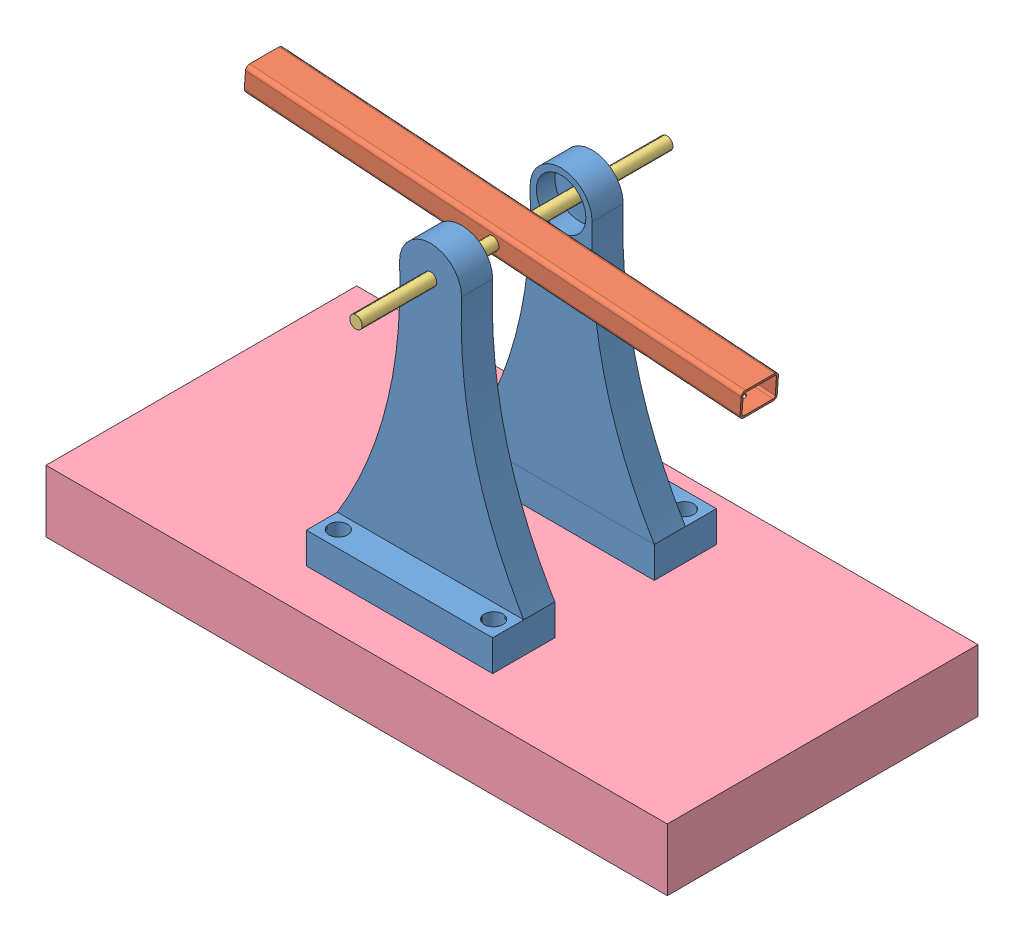
SolidWorks assembly Montaj3, configuration Varsayılan. Lengths in mm.
Overall size (200 120 100.54).
5 component instances, 4 part files, 9 mates.
Components (placement in the parent):
- Parça3-1: Parça3 [Varsayılan] at (-54.6367 -205.5653 460.3065) x (1 0 0.00036) z (-0.00036 0 1) size (60 100 20)
- profil-1: profil [Varsayılan<Makinelenmiş Olarak>] at (35.1609 -131.1707 476.3389) x (-0.997542 0.070068 -0.000359) z (0.070068 0.997542 0.000025) size (160 12 8)
- Parça3-3: Parça3 [Varsayılan] at (-34.6482 -205.5653 492.3137) x (-1 0 -0.00036) z (0.00036 0 -1) size (60 100 20)
- saplama-1: saplama [Varsayılan] at (-44.6244 -125.5653 426.3101) x (0.443181 0.896432 0.00016) z (-0.00036 0 1) size (4.1 4 100.35)
- base-1: base [Default] at (-44.6314 -235.5653 476.1191) size (200 20 100)
Mates (geometry in assembly coordinates):
- Eş Merkezli1: concentric aligned: cylinder of Parça3-1 through (-44.6331 -125.5653 450.3101) axis (-0.00036 0 1) radius 2; cylinder of profil-1 through (-44.6388 -125.5653 466.3101) axis (-0.00036 0 1) radius 2
- Eş Merkezli2: concentric anti-aligned: cylinder of profil-1 through (-44.6388 -125.5653 466.3101) axis (-0.00036 0 1) radius 2; cylinder of Parça3-3 through (-44.6518 -125.5653 502.3101) axis (0.00036 0 -1) radius 2
- Uzaklık1: distance = 10 mm anti-aligned: plane of Parça3-3 through (-30.5299 -167.4779 492.3152) normal (0.00036 0 -1); plane of profil-1 through (-124.6386 -122.6731 482.2813) normal (-0.00036 0 1)
- Uzaklık2: distance = 10 mm anti-aligned: plane of Parça3-1 through (-58.755 -167.4779 460.305) normal (-0.00036 0 1); plane of profil-1 through (-124.2531 -117.2465 470.2814) normal (0.00036 0 -1)
- Paralel1: parallel aligned: plane of Parça3-1 through (-54.6367 -215.5653 460.3065) normal (0 -1 0); plane of Parça3-3 through (-34.6482 -215.5653 492.3137) normal (0 -1 0)
- Eş Merkezli3: concentric anti-aligned: cylinder of profil-1 through (-44.6388 -125.5653 466.3101) axis (-0.00036 0 1) radius 2; cylinder of saplama-1 through (-44.6605 -125.5653 526.3101) axis (0.00036 0 -1) radius 2
- Genişlik1: width aligned: plane of saplama-1 through (-44.6605 -125.5653 526.3101) normal (-0.00036 0 1); plane of profil-1 through (-44.6244 -125.5653 426.3101) normal (0.00036 0 -1); plane of saplama-1 through (-124.6386 -122.6731 482.2813) normal (-0.00036 0 1); plane of profil-1 through (-124.2531 -117.2465 470.2814) normal (0.00036 0 -1)
- Concentric5: concentric aligned: circle of Parça3-1; circle of saplama-1
- Coincident9: coincident aligned: circle of Parça3-1; circle of base-1
